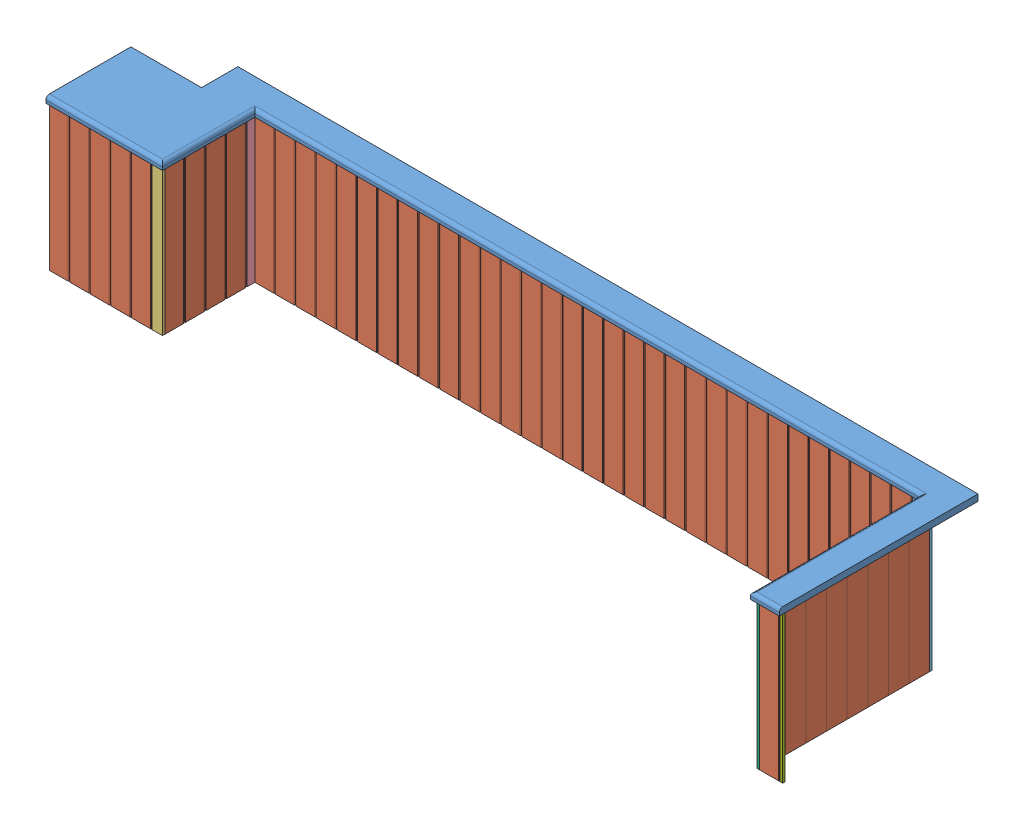
SolidWorks assembly Brüstung, configuration Standard. Lengths in mm.
Overall size (4890 900 1170).
56 component instances, 7 part files, 166 mates.
Components (placement in the parent):
- Platte-1: Platte [Standard] at (1989.1315 795.0064 4189) size (4774 38 1170)
- Wandbrett-1: Wandbrett [Standard] at (-2724.3685 795.0064 4876) x (1 0 0) z (0 0 -1) size (131 862 14)
- Wandbrett-2: Wandbrett [Standard] at (-2603.3685 795.0064 4876) x (1 0 0) z (0 0 -1) size (131 862 14)
- Wandbrett-3: Wandbrett [Standard] at (-2482.3685 795.0064 4876) x (1 0 0) z (0 0 -1) size (131 862 14)
- Wandbrett-4: Wandbrett [Standard] at (-2361.3685 795.0064 4876) x (1 0 0) z (0 0 -1) size (131 862 14)
- Wandbrett-Ecke1-1: Wandbrett-Ecke1 [Standard] at (-2119.3685 795.0064 4876) x (1 0 0) z (0 0 -1) size (131 862 14)
- Wandbrett-6: Wandbrett [Standard] at (-2125.8685 795.0064 4808.5) x (0 0 -1) z (-1 0 0) size (131 862 14)
- Wandbrett-7: Wandbrett [Standard] at (-2125.8685 795.0064 4687.5) x (0 0 -1) z (-1 0 0) size (131 862 14)
- Wandbrett-8: Wandbrett [Standard] at (-2125.8685 795.0064 4566.5) x (0 0 -1) z (-1 0 0) size (131 862 14)
- Wandbrett-9: Wandbrett [Standard] at (-2125.8685 795.0064 4445.5) x (0 0 -1) z (-1 0 0) size (131 862 14)
- Wandbrett-Ecke2-1: Wandbrett-Ecke2 [Standard] at (-2125.8685 795.0064 4324.5) x (0 0 -1) z (-1 0 0) size (60 862 14)
- Wandbrett-11: Wandbrett [Standard] at (-2058.3685 795.0064 4332) x (1 0 0) z (0 0 -1) size (131 862 14)
- Wandbrett-12: Wandbrett [Standard] at (-1937.3685 795.0064 4332) x (1 0 0) z (0 0 -1) size (131 862 14)
- Wandbrett-13: Wandbrett [Standard] at (-1816.3685 795.0064 4332) x (1 0 0) z (0 0 -1) size (131 862 14)
- Wandbrett-14: Wandbrett [Standard] at (-1695.3685 795.0064 4332) x (1 0 0) z (0 0 -1) size (131 862 14)
- Wandbrett-15: Wandbrett [Standard] at (-1574.3685 795.0064 4332) x (1 0 0) z (0 0 -1) size (131 862 14)
- Wandbrett-16: Wandbrett [Standard] at (-1453.3685 795.0064 4332) x (1 0 0) z (0 0 -1) size (131 862 14)
- Wandbrett-17: Wandbrett [Standard] at (-1332.3685 795.0064 4332) x (1 0 0) z (0 0 -1) size (131 862 14)
- Wandbrett-18: Wandbrett [Standard] at (-1211.3685 795.0064 4332) x (1 0 0) z (0 0 -1) size (131 862 14)
- Wandbrett-19: Wandbrett [Standard] at (-1090.3685 795.0064 4332) x (1 0 0) z (0 0 -1) size (131 862 14)
- Wandbrett-20: Wandbrett [Standard] at (-969.3685 795.0064 4332) x (1 0 0) z (0 0 -1) size (131 862 14)
- Wandbrett-21: Wandbrett [Standard] at (-848.3685 795.0064 4332) x (1 0 0) z (0 0 -1) size (131 862 14)
- Wandbrett-22: Wandbrett [Standard] at (-727.3685 795.0064 4332) x (1 0 0) z (0 0 -1) size (131 862 14)
- Wandbrett-23: Wandbrett [Standard] at (-606.3685 795.0064 4332) x (1 0 0) z (0 0 -1) size (131 862 14)
- Wandbrett-24: Wandbrett [Standard] at (-485.3685 795.0064 4332) x (1 0 0) z (0 0 -1) size (131 862 14)
- Wandbrett-25: Wandbrett [Standard] at (-364.3685 795.0064 4332) x (1 0 0) z (0 0 -1) size (131 862 14)
- Wandbrett-26: Wandbrett [Standard] at (-243.3685 795.0064 4332) x (1 0 0) z (0 0 -1) size (131 862 14)
- Wandbrett-27: Wandbrett [Standard] at (-122.3685 795.0064 4332) x (1 0 0) z (0 0 -1) size (131 862 14)
- Wandbrett-28: Wandbrett [Standard] at (-1.3685 795.0064 4332) x (1 0 0) z (0 0 -1) size (131 862 14)
- Wandbrett-29: Wandbrett [Standard] at (119.6315 795.0064 4332) x (1 0 0) z (0 0 -1) size (131 862 14)
- Wandbrett-30: Wandbrett [Standard] at (240.6315 795.0064 4332) x (1 0 0) z (0 0 -1) size (131 862 14)
- Wandbrett-31: Wandbrett [Standard] at (361.6315 795.0064 4332) x (1 0 0) z (0 0 -1) size (131 862 14)
- Wandbrett-32: Wandbrett [Standard] at (482.6315 795.0064 4332) x (1 0 0) z (0 0 -1) size (131 862 14)
- Wandbrett-33: Wandbrett [Standard] at (603.6315 795.0064 4332) x (1 0 0) z (0 0 -1) size (131 862 14)
- Wandbrett-34: Wandbrett [Standard] at (724.6315 795.0064 4332) x (1 0 0) z (0 0 -1) size (131 862 14)
- Wandbrett-35: Wandbrett [Standard] at (845.6315 795.0064 4332) x (1 0 0) z (0 0 -1) size (131 862 14)
- Wandbrett-36: Wandbrett [Standard] at (966.6315 795.0064 4332) x (1 0 0) z (0 0 -1) size (131 862 14)
- Wandbrett-37: Wandbrett [Standard] at (1087.6315 795.0064 4332) x (1 0 0) z (0 0 -1) size (131 862 14)
- Wandbrett-38: Wandbrett [Standard] at (1208.6315 795.0064 4332) x (1 0 0) z (0 0 -1) size (131 862 14)
- Wandbrett-39: Wandbrett [Standard] at (1329.6315 795.0064 4332) x (1 0 0) z (0 0 -1) size (131 862 14)
- Wandbrett-40: Wandbrett [Standard] at (1450.6315 795.0064 4332) x (1 0 0) z (0 0 -1) size (131 862 14)
- Wandbrett-41: Wandbrett [Standard] at (1571.6315 795.0064 4332) x (1 0 0) z (0 0 -1) size (131 862 14)
- Wandbrett-42: Wandbrett [Standard] at (1692.6315 795.0064 4332) x (1 0 0) z (0 0 -1) size (131 862 14)
- Wandbrett-43: Wandbrett [Standard] at (-2240.3685 795.0064 4876) x (1 0 0) z (0 0 -1) size (131 862 14)
- Wandbrett-Ecke3-1: Wandbrett-Ecke3 [Standard] at (1813.6315 795.0064 4332) x (1 0 0) z (0 0 -1) size (131 862 14)
- Wandbrett-44: Wandbrett [Standard] at (1846.1315 795.0064 4399.5) x (0 0 1) z (1 0 0) size (131 862 14)
- Wandbrett-45: Wandbrett [Standard] at (1846.1315 795.0064 4520.5) x (0 0 1) z (1 0 0) size (131 862 14)
- Wandbrett-46: Wandbrett [Standard] at (1846.1315 795.0064 4641.5) x (0 0 1) z (1 0 0) size (131 862 14)
- Wandbrett-47: Wandbrett [Standard] at (1846.1315 795.0064 4762.5) x (0 0 1) z (1 0 0) size (131 862 14)
- Wandbrett-48: Wandbrett [Standard] at (1846.1315 795.0064 4883.5) x (0 0 1) z (1 0 0) size (131 862 14)
- Wandbrett-49: Wandbrett [Standard] at (1846.1315 795.0064 5004.5) x (0 0 1) z (1 0 0) size (131 862 14)
- Wandbrett-50: Wandbrett [Standard] at (1846.1315 795.0064 5125.5) x (0 0 1) z (1 0 0) size (131 862 14)
- Wandbrett-51: Wandbrett [Standard] at (1846.1315 795.0064 5246.5) x (0 0 1) z (1 0 0) size (131 862 14)
- Wandbrett-Ecke4-1: Wandbrett-Ecke4 [Standard] at (1846.1315 795.0064 5367.5) x (0 0 1) z (1 0 0) size (32 862 14)
- Wandbrett-52: Wandbrett [Standard] at (1913.6315 795.0064 5332) x (1 0 0) z (0 0 -1) size (131 862 14)
- Wandbrett-Ecke5-1: Wandbrett-Ecke5 [Standard] at (2034.6315 795.0064 5332) x (1 0 0) z (0 0 -1) size (131 862 14)
Mates (geometry in assembly coordinates):
- Deckungsgleich1: coincident anti-aligned: plane of Platte-1 through (1989.1315 795.0064 4189) normal (0 -1 0); plane of Wandbrett-1 through (-2674.8685 795.0064 4879) normal (0 1 0)
- Deckungsgleich2: coincident anti-aligned: plane of Platte-1 through (1989.1315 795.0064 4189) normal (0 -1 0); plane of Wandbrett-2 through (-2553.8685 795.0064 4879) normal (0 1 0)
- Deckungsgleich3: coincident anti-aligned: plane of Platte-1 through (1989.1315 795.0064 4189) normal (0 -1 0); plane of Wandbrett-3 through (-2432.8685 795.0064 4879) normal (0 1 0)
- Deckungsgleich4: coincident anti-aligned: plane of Platte-1 through (1989.1315 795.0064 4189) normal (0 -1 0); plane of Wandbrett-4 through (-2311.8685 795.0064 4879) normal (0 1 0)
- Parallel1: parallel aligned: plane of Platte-1 through (-2784.8685 833.0064 4903) normal (0 0 1); plane of Wandbrett-1 through (-2674.8685 -66.9936 4883) normal (0 0 1)
- Abstand2: distance = 20 mm aligned: plane of Wandbrett-1 through (-2674.8685 -66.9936 4883) normal (0 0 1); plane of Platte-1 through (-2784.8685 833.0064 4903) normal (0 0 1)
- Deckungsgleich9: coincident aligned: plane of Platte-1 through (-2784.8685 833.0064 4903) normal (-1 0 0); plane of Wandbrett-1 through (-2784.8685 -66.9936 4869) normal (-1 0 0)
- Deckungsgleich10: coincident anti-aligned: plane of Wandbrett-1 through (-2663.8685 -66.9936 4878) normal (0 0 1); plane of Wandbrett-2 through (-2653.8685 -66.9936 4878) normal (0 0 -1)
- Deckungsgleich11: coincident anti-aligned: plane of Wandbrett-2 through (-2542.8685 -66.9936 4878) normal (0 0 1); plane of Wandbrett-3 through (-2532.8685 -66.9936 4878) normal (0 0 -1)
- Deckungsgleich12: coincident anti-aligned: plane of Wandbrett-3 through (-2421.8685 -66.9936 4878) normal (0 0 1); plane of Wandbrett-4 through (-2411.8685 -66.9936 4878) normal (0 0 -1)
- Deckungsgleich14: coincident anti-aligned: plane of Wandbrett-1 through (-2653.8685 -66.9936 4878) normal (1 0 0); plane of Wandbrett-2 through (-2653.8685 -66.9936 4874) normal (-1 0 0)
- Deckungsgleich15: coincident anti-aligned: plane of Wandbrett-2 through (-2532.8685 -66.9936 4878) normal (1 0 0); plane of Wandbrett-3 through (-2532.8685 -66.9936 4874) normal (-1 0 0)
- Deckungsgleich16: coincident anti-aligned: plane of Wandbrett-3 through (-2411.8685 -66.9936 4878) normal (1 0 0); plane of Wandbrett-4 through (-2411.8685 -66.9936 4874) normal (-1 0 0)
- Deckungsgleich18: coincident anti-aligned: plane of Platte-1 through (1989.1315 795.0064 4189) normal (0 -1 0); plane of Wandbrett-Ecke1-1 through (-2069.8685 795.0064 4879) normal (0 1 0)
- Deckungsgleich21: coincident anti-aligned: plane of Platte-1 through (1989.1315 795.0064 4189) normal (0 -1 0); plane of Wandbrett-6 through (-2122.8685 795.0064 4759) normal (0 1 0)
- Deckungsgleich22: coincident anti-aligned: plane of Platte-1 through (1989.1315 795.0064 4189) normal (0 -1 0); plane of Wandbrett-7 through (-2122.8685 795.0064 4638) normal (0 1 0)
- Deckungsgleich23: coincident anti-aligned: plane of Platte-1 through (1989.1315 795.0064 4189) normal (0 -1 0); plane of Wandbrett-8 through (-2122.8685 795.0064 4517) normal (0 1 0)
- Deckungsgleich24: coincident anti-aligned: plane of Platte-1 through (1989.1315 795.0064 4189) normal (0 -1 0); plane of Wandbrett-9 through (-2122.8685 795.0064 4396) normal (0 1 0)
- Deckungsgleich26: coincident anti-aligned: plane of Wandbrett-Ecke1-1 through (-2058.8685 -66.9936 4869) normal (0 0 -1); plane of Wandbrett-6 through (-2132.8685 -66.9936 4869) normal (0 0 1)
- Deckungsgleich27: coincident aligned: plane of Wandbrett-Ecke1-1 through (-2118.8685 -204.9936 4869) normal (1 0 0); plane of Wandbrett-6 through (-2118.8685 -66.9936 4759) normal (1 0 0)
- Deckungsgleich28: coincident anti-aligned: plane of Wandbrett-6 through (-2123.8685 -66.9936 4748) normal (1 0 0); plane of Wandbrett-7 through (-2123.8685 -66.9936 4738) normal (-1 0 0)
- Deckungsgleich29: coincident anti-aligned: plane of Wandbrett-7 through (-2123.8685 -66.9936 4627) normal (1 0 0); plane of Wandbrett-8 through (-2123.8685 -66.9936 4617) normal (-1 0 0)
- Deckungsgleich30: coincident anti-aligned: plane of Wandbrett-8 through (-2123.8685 -66.9936 4506) normal (1 0 0); plane of Wandbrett-9 through (-2123.8685 -66.9936 4496) normal (-1 0 0)
- Deckungsgleich32: coincident anti-aligned: plane of Wandbrett-6 through (-2123.8685 -66.9936 4738) normal (0 0 -1); plane of Wandbrett-7 through (-2127.8685 -66.9936 4738) normal (0 0 1)
- Deckungsgleich33: coincident anti-aligned: plane of Wandbrett-7 through (-2123.8685 -66.9936 4617) normal (0 0 -1); plane of Wandbrett-8 through (-2127.8685 -66.9936 4617) normal (0 0 1)
- Deckungsgleich34: coincident anti-aligned: plane of Wandbrett-8 through (-2123.8685 -66.9936 4496) normal (0 0 -1); plane of Wandbrett-9 through (-2127.8685 -66.9936 4496) normal (0 0 1)
- Deckungsgleich36: coincident anti-aligned: plane of Platte-1 through (1989.1315 795.0064 4189) normal (0 -1 0); plane of Wandbrett-Ecke2-1 through (-2122.8685 795.0064 4275) normal (0 1 0)
- Deckungsgleich37: coincident anti-aligned: plane of Wandbrett-9 through (-2123.8685 -66.9936 4385) normal (1 0 0); plane of Wandbrett-Ecke2-1 through (-2123.8685 -66.9936 4375) normal (-1 0 0)
- Deckungsgleich38: coincident anti-aligned: plane of Wandbrett-9 through (-2123.8685 -66.9936 4375) normal (0 0 -1); plane of Wandbrett-Ecke2-1 through (-2127.8685 -66.9936 4375) normal (0 0 1)
- Deckungsgleich39: coincident anti-aligned: plane of Platte-1 through (1989.1315 795.0064 4189) normal (0 -1 0); plane of Wandbrett-11 through (-2008.8685 795.0064 4335) normal (0 1 0)
- Deckungsgleich40: coincident anti-aligned: plane of Platte-1 through (1989.1315 795.0064 4189) normal (0 -1 0); plane of Wandbrett-12 through (-1887.8685 795.0064 4335) normal (0 1 0)
- Deckungsgleich41: coincident anti-aligned: plane of Platte-1 through (1989.1315 795.0064 4189) normal (0 -1 0); plane of Wandbrett-13 through (-1766.8685 795.0064 4335) normal (0 1 0)
- Deckungsgleich42: coincident anti-aligned: plane of Platte-1 through (1989.1315 795.0064 4189) normal (0 -1 0); plane of Wandbrett-14 through (-1645.8685 795.0064 4335) normal (0 1 0)
- Deckungsgleich43: coincident anti-aligned: plane of Platte-1 through (1989.1315 795.0064 4189) normal (0 -1 0); plane of Wandbrett-15 through (-1524.8685 795.0064 4335) normal (0 1 0)
- Deckungsgleich44: coincident anti-aligned: plane of Platte-1 through (1989.1315 795.0064 4189) normal (0 -1 0); plane of Wandbrett-16 through (-1403.8685 795.0064 4335) normal (0 1 0)
- Deckungsgleich45: coincident anti-aligned: plane of Platte-1 through (1989.1315 795.0064 4189) normal (0 -1 0); plane of Wandbrett-17 through (-1282.8685 795.0064 4335) normal (0 1 0)
- Deckungsgleich46: coincident anti-aligned: plane of Platte-1 through (1989.1315 795.0064 4189) normal (0 -1 0); plane of Wandbrett-18 through (-1161.8685 795.0064 4335) normal (0 1 0)
- Deckungsgleich47: coincident anti-aligned: plane of Platte-1 through (1989.1315 795.0064 4189) normal (0 -1 0); plane of Wandbrett-19 through (-1040.8685 795.0064 4335) normal (0 1 0)
- Deckungsgleich48: coincident anti-aligned: plane of Platte-1 through (1989.1315 795.0064 4189) normal (0 -1 0); plane of Wandbrett-20 through (-919.8685 795.0064 4335) normal (0 1 0)
- Deckungsgleich49: coincident anti-aligned: plane of Platte-1 through (1989.1315 795.0064 4189) normal (0 -1 0); plane of Wandbrett-21 through (-798.8685 795.0064 4335) normal (0 1 0)
- Deckungsgleich50: coincident anti-aligned: plane of Platte-1 through (1989.1315 795.0064 4189) normal (0 -1 0); plane of Wandbrett-22 through (-677.8685 795.0064 4335) normal (0 1 0)
- Deckungsgleich51: coincident anti-aligned: plane of Platte-1 through (1989.1315 795.0064 4189) normal (0 -1 0); plane of Wandbrett-23 through (-556.8685 795.0064 4335) normal (0 1 0)
- Deckungsgleich52: coincident anti-aligned: plane of Platte-1 through (1989.1315 795.0064 4189) normal (0 -1 0); plane of Wandbrett-24 through (-435.8685 795.0064 4335) normal (0 1 0)
- Deckungsgleich53: coincident anti-aligned: plane of Platte-1 through (1989.1315 795.0064 4189) normal (0 -1 0); plane of Wandbrett-25 through (-314.8685 795.0064 4335) normal (0 1 0)
- Deckungsgleich54: coincident anti-aligned: plane of Platte-1 through (1989.1315 795.0064 4189) normal (0 -1 0); plane of Wandbrett-26 through (-193.8685 795.0064 4335) normal (0 1 0)
- Deckungsgleich55: coincident anti-aligned: plane of Platte-1 through (1989.1315 795.0064 4189) normal (0 -1 0); plane of Wandbrett-27 through (-72.8685 795.0064 4335) normal (0 1 0)
- Deckungsgleich56: coincident anti-aligned: plane of Platte-1 through (1989.1315 795.0064 4189) normal (0 -1 0); plane of Wandbrett-28 through (48.1315 795.0064 4335) normal (0 1 0)
- Deckungsgleich57: coincident anti-aligned: plane of Platte-1 through (1989.1315 795.0064 4189) normal (0 -1 0); plane of Wandbrett-29 through (169.1315 795.0064 4335) normal (0 1 0)
- Deckungsgleich58: coincident anti-aligned: plane of Platte-1 through (1989.1315 795.0064 4189) normal (0 -1 0); plane of Wandbrett-30 through (290.1315 795.0064 4335) normal (0 1 0)
- Deckungsgleich59: coincident anti-aligned: plane of Platte-1 through (1989.1315 795.0064 4189) normal (0 -1 0); plane of Wandbrett-31 through (411.1315 795.0064 4335) normal (0 1 0)
- Deckungsgleich60: coincident anti-aligned: plane of Platte-1 through (1989.1315 795.0064 4189) normal (0 -1 0); plane of Wandbrett-32 through (532.1315 795.0064 4335) normal (0 1 0)
- Deckungsgleich61: coincident anti-aligned: plane of Platte-1 through (1989.1315 795.0064 4189) normal (0 -1 0); plane of Wandbrett-33 through (653.1315 795.0064 4335) normal (0 1 0)
- Deckungsgleich62: coincident anti-aligned: plane of Platte-1 through (1989.1315 795.0064 4189) normal (0 -1 0); plane of Wandbrett-34 through (774.1315 795.0064 4335) normal (0 1 0)
- Deckungsgleich63: coincident anti-aligned: plane of Platte-1 through (1989.1315 795.0064 4189) normal (0 -1 0); plane of Wandbrett-35 through (895.1315 795.0064 4335) normal (0 1 0)
- Deckungsgleich64: coincident anti-aligned: plane of Platte-1 through (1989.1315 795.0064 4189) normal (0 -1 0); plane of Wandbrett-36 through (1016.1315 795.0064 4335) normal (0 1 0)
- Deckungsgleich65: coincident anti-aligned: plane of Platte-1 through (1989.1315 795.0064 4189) normal (0 -1 0); plane of Wandbrett-37 through (1137.1315 795.0064 4335) normal (0 1 0)
- Deckungsgleich66: coincident anti-aligned: plane of Platte-1 through (1989.1315 795.0064 4189) normal (0 -1 0); plane of Wandbrett-38 through (1258.1315 795.0064 4335) normal (0 1 0)
- Deckungsgleich67: coincident anti-aligned: plane of Platte-1 through (1989.1315 795.0064 4189) normal (0 -1 0); plane of Wandbrett-39 through (1379.1315 795.0064 4335) normal (0 1 0)
- Deckungsgleich68: coincident anti-aligned: plane of Platte-1 through (1989.1315 795.0064 4189) normal (0 -1 0); plane of Wandbrett-40 through (1500.1315 795.0064 4335) normal (0 1 0)
- Deckungsgleich69: coincident anti-aligned: plane of Platte-1 through (1989.1315 795.0064 4189) normal (0 -1 0); plane of Wandbrett-41 through (1621.1315 795.0064 4335) normal (0 1 0)
- Deckungsgleich70: coincident anti-aligned: plane of Platte-1 through (1989.1315 795.0064 4189) normal (0 -1 0); plane of Wandbrett-42 through (1742.1315 795.0064 4335) normal (0 1 0)
- Deckungsgleich71: coincident anti-aligned: plane of Wandbrett-Ecke2-1 through (-2118.8685 -66.9936 4275) normal (1 0 0); plane of Wandbrett-11 through (-2118.8685 -66.9936 4334) normal (-1 0 0)
- Deckungsgleich72: coincident anti-aligned: plane of Wandbrett-11 through (-1997.8685 -66.9936 4334) normal (0 0 1); plane of Wandbrett-12 through (-1987.8685 -66.9936 4334) normal (0 0 -1)
- Deckungsgleich73: coincident anti-aligned: plane of Wandbrett-12 through (-1876.8685 -66.9936 4334) normal (0 0 1); plane of Wandbrett-13 through (-1866.8685 -66.9936 4334) normal (0 0 -1)
- Deckungsgleich74: coincident anti-aligned: plane of Wandbrett-13 through (-1755.8685 -66.9936 4334) normal (0 0 1); plane of Wandbrett-14 through (-1745.8685 -66.9936 4334) normal (0 0 -1)
- Deckungsgleich75: coincident anti-aligned: plane of Wandbrett-14 through (-1634.8685 -66.9936 4334) normal (0 0 1); plane of Wandbrett-15 through (-1624.8685 -66.9936 4334) normal (0 0 -1)
- Deckungsgleich76: coincident anti-aligned: plane of Wandbrett-15 through (-1513.8685 -66.9936 4334) normal (0 0 1); plane of Wandbrett-16 through (-1503.8685 -66.9936 4334) normal (0 0 -1)
- Deckungsgleich77: coincident anti-aligned: plane of Wandbrett-16 through (-1392.8685 -66.9936 4334) normal (0 0 1); plane of Wandbrett-17 through (-1382.8685 -66.9936 4334) normal (0 0 -1)
- Deckungsgleich78: coincident anti-aligned: plane of Wandbrett-17 through (-1271.8685 -66.9936 4334) normal (0 0 1); plane of Wandbrett-18 through (-1261.8685 -66.9936 4334) normal (0 0 -1)
- Deckungsgleich79: coincident anti-aligned: plane of Wandbrett-18 through (-1150.8685 -66.9936 4334) normal (0 0 1); plane of Wandbrett-19 through (-1140.8685 -66.9936 4334) normal (0 0 -1)
- Deckungsgleich80: coincident anti-aligned: plane of Wandbrett-19 through (-1029.8685 -66.9936 4334) normal (0 0 1); plane of Wandbrett-20 through (-1019.8685 -66.9936 4334) normal (0 0 -1)
- Deckungsgleich81: coincident anti-aligned: plane of Wandbrett-20 through (-908.8685 -66.9936 4334) normal (0 0 1); plane of Wandbrett-21 through (-898.8685 -66.9936 4334) normal (0 0 -1)
- Deckungsgleich82: coincident anti-aligned: plane of Wandbrett-21 through (-787.8685 -66.9936 4334) normal (0 0 1); plane of Wandbrett-22 through (-777.8685 -66.9936 4334) normal (0 0 -1)
- Deckungsgleich83: coincident anti-aligned: plane of Wandbrett-22 through (-666.8685 -66.9936 4334) normal (0 0 1); plane of Wandbrett-23 through (-656.8685 -66.9936 4334) normal (0 0 -1)
- Deckungsgleich84: coincident anti-aligned: plane of Wandbrett-23 through (-545.8685 -66.9936 4334) normal (0 0 1); plane of Wandbrett-24 through (-535.8685 -66.9936 4334) normal (0 0 -1)
- Deckungsgleich85: coincident anti-aligned: plane of Wandbrett-24 through (-424.8685 -66.9936 4334) normal (0 0 1); plane of Wandbrett-25 through (-414.8685 -66.9936 4334) normal (0 0 -1)
- Deckungsgleich86: coincident anti-aligned: plane of Wandbrett-25 through (-303.8685 -66.9936 4334) normal (0 0 1); plane of Wandbrett-26 through (-293.8685 -66.9936 4334) normal (0 0 -1)
- Deckungsgleich87: coincident anti-aligned: plane of Wandbrett-26 through (-182.8685 -66.9936 4334) normal (0 0 1); plane of Wandbrett-27 through (-172.8685 -66.9936 4334) normal (0 0 -1)
- Deckungsgleich88: coincident anti-aligned: plane of Wandbrett-27 through (-61.8685 -66.9936 4334) normal (0 0 1); plane of Wandbrett-28 through (-51.8685 -66.9936 4334) normal (0 0 -1)
- Deckungsgleich90: coincident anti-aligned: plane of Wandbrett-28 through (59.1315 -66.9936 4334) normal (0 0 1); plane of Wandbrett-29 through (69.1315 -66.9936 4334) normal (0 0 -1)
- Deckungsgleich91: coincident anti-aligned: plane of Wandbrett-29 through (180.1315 -66.9936 4334) normal (0 0 1); plane of Wandbrett-30 through (190.1315 -66.9936 4334) normal (0 0 -1)
- Deckungsgleich92: coincident anti-aligned: plane of Wandbrett-30 through (301.1315 -66.9936 4334) normal (0 0 1); plane of Wandbrett-31 through (311.1315 -66.9936 4334) normal (0 0 -1)
- Deckungsgleich93: coincident anti-aligned: plane of Wandbrett-31 through (422.1315 -66.9936 4334) normal (0 0 1); plane of Wandbrett-32 through (432.1315 -66.9936 4334) normal (0 0 -1)
- Deckungsgleich94: coincident anti-aligned: plane of Wandbrett-32 through (543.1315 -66.9936 4334) normal (0 0 1); plane of Wandbrett-33 through (553.1315 -66.9936 4334) normal (0 0 -1)
- Deckungsgleich95: coincident anti-aligned: plane of Wandbrett-33 through (664.1315 -66.9936 4334) normal (0 0 1); plane of Wandbrett-34 through (674.1315 -66.9936 4334) normal (0 0 -1)
- Deckungsgleich96: coincident anti-aligned: plane of Wandbrett-34 through (785.1315 -66.9936 4334) normal (0 0 1); plane of Wandbrett-35 through (795.1315 -66.9936 4334) normal (0 0 -1)
- Deckungsgleich97: coincident anti-aligned: plane of Wandbrett-35 through (906.1315 -66.9936 4334) normal (0 0 1); plane of Wandbrett-36 through (916.1315 -66.9936 4334) normal (0 0 -1)
- Deckungsgleich98: coincident anti-aligned: plane of Wandbrett-36 through (1027.1315 -66.9936 4334) normal (0 0 1); plane of Wandbrett-37 through (1037.1315 -66.9936 4334) normal (0 0 -1)
- Deckungsgleich99: coincident anti-aligned: plane of Wandbrett-37 through (1148.1315 -66.9936 4334) normal (0 0 1); plane of Wandbrett-38 through (1158.1315 -66.9936 4334) normal (0 0 -1)
- Deckungsgleich100: coincident anti-aligned: plane of Wandbrett-38 through (1269.1315 -66.9936 4334) normal (0 0 1); plane of Wandbrett-39 through (1279.1315 -66.9936 4334) normal (0 0 -1)
- Deckungsgleich101: coincident anti-aligned: plane of Wandbrett-39 through (1390.1315 -66.9936 4334) normal (0 0 1); plane of Wandbrett-40 through (1400.1315 -66.9936 4334) normal (0 0 -1)
- Deckungsgleich102: coincident anti-aligned: plane of Wandbrett-40 through (1511.1315 -66.9936 4334) normal (0 0 1); plane of Wandbrett-41 through (1521.1315 -66.9936 4334) normal (0 0 -1)
- Deckungsgleich103: coincident anti-aligned: plane of Wandbrett-41 through (1632.1315 -66.9936 4334) normal (0 0 1); plane of Wandbrett-42 through (1642.1315 -66.9936 4334) normal (0 0 -1)
- Deckungsgleich104: coincident aligned: plane of Wandbrett-Ecke2-1 through (-2118.8685 -204.9936 4325) normal (0 0 -1); plane of Wandbrett-11 through (-1997.8685 -66.9936 4325) normal (0 0 -1)
- Deckungsgleich105: coincident anti-aligned: plane of Wandbrett-11 through (-1987.8685 -66.9936 4334) normal (1 0 0); plane of Wandbrett-12 through (-1987.8685 -66.9936 4330) normal (-1 0 0)
- Deckungsgleich106: coincident anti-aligned: plane of Wandbrett-12 through (-1866.8685 -66.9936 4334) normal (1 0 0); plane of Wandbrett-13 through (-1866.8685 -66.9936 4330) normal (-1 0 0)
- Deckungsgleich107: coincident anti-aligned: plane of Wandbrett-13 through (-1745.8685 -66.9936 4334) normal (1 0 0); plane of Wandbrett-14 through (-1745.8685 -66.9936 4330) normal (-1 0 0)
- Deckungsgleich108: coincident anti-aligned: plane of Wandbrett-14 through (-1624.8685 -66.9936 4334) normal (1 0 0); plane of Wandbrett-15 through (-1624.8685 -66.9936 4330) normal (-1 0 0)
- Deckungsgleich109: coincident anti-aligned: plane of Wandbrett-15 through (-1503.8685 -66.9936 4334) normal (1 0 0); plane of Wandbrett-16 through (-1503.8685 -66.9936 4330) normal (-1 0 0)
- Deckungsgleich110: coincident anti-aligned: plane of Wandbrett-16 through (-1382.8685 -66.9936 4334) normal (1 0 0); plane of Wandbrett-17 through (-1382.8685 -66.9936 4330) normal (-1 0 0)
- Deckungsgleich111: coincident anti-aligned: plane of Wandbrett-17 through (-1261.8685 -66.9936 4334) normal (1 0 0); plane of Wandbrett-18 through (-1261.8685 -66.9936 4330) normal (-1 0 0)
- Deckungsgleich112: coincident anti-aligned: plane of Wandbrett-18 through (-1140.8685 -66.9936 4334) normal (1 0 0); plane of Wandbrett-19 through (-1140.8685 -66.9936 4330) normal (-1 0 0)
- Deckungsgleich113: coincident anti-aligned: plane of Wandbrett-19 through (-1019.8685 -66.9936 4334) normal (1 0 0); plane of Wandbrett-20 through (-1019.8685 -66.9936 4330) normal (-1 0 0)
- Deckungsgleich114: coincident anti-aligned: plane of Wandbrett-20 through (-898.8685 -66.9936 4334) normal (1 0 0); plane of Wandbrett-21 through (-898.8685 -66.9936 4330) normal (-1 0 0)
- Deckungsgleich115: coincident anti-aligned: plane of Wandbrett-21 through (-777.8685 -66.9936 4334) normal (1 0 0); plane of Wandbrett-22 through (-777.8685 -66.9936 4330) normal (-1 0 0)
- Deckungsgleich117: coincident anti-aligned: plane of Wandbrett-22 through (-656.8685 -66.9936 4334) normal (1 0 0); plane of Wandbrett-23 through (-656.8685 -66.9936 4330) normal (-1 0 0)
- Deckungsgleich118: coincident anti-aligned: plane of Wandbrett-23 through (-535.8685 -66.9936 4334) normal (1 0 0); plane of Wandbrett-24 through (-535.8685 -66.9936 4330) normal (-1 0 0)
- Deckungsgleich119: coincident anti-aligned: plane of Wandbrett-24 through (-414.8685 -66.9936 4334) normal (1 0 0); plane of Wandbrett-25 through (-414.8685 -66.9936 4330) normal (-1 0 0)
- Deckungsgleich121: coincident anti-aligned: plane of Wandbrett-25 through (-293.8685 -66.9936 4334) normal (1 0 0); plane of Wandbrett-26 through (-293.8685 -66.9936 4330) normal (-1 0 0)
- Deckungsgleich122: coincident anti-aligned: plane of Wandbrett-26 through (-172.8685 -66.9936 4334) normal (1 0 0); plane of Wandbrett-27 through (-172.8685 -66.9936 4330) normal (-1 0 0)
- Deckungsgleich123: coincident anti-aligned: plane of Wandbrett-27 through (-51.8685 -66.9936 4334) normal (1 0 0); plane of Wandbrett-28 through (-51.8685 -66.9936 4330) normal (-1 0 0)
- Deckungsgleich124: coincident anti-aligned: plane of Wandbrett-28 through (69.1315 -66.9936 4334) normal (1 0 0); plane of Wandbrett-29 through (69.1315 -66.9936 4330) normal (-1 0 0)
- Deckungsgleich125: coincident anti-aligned: plane of Wandbrett-29 through (190.1315 -66.9936 4334) normal (1 0 0); plane of Wandbrett-30 through (190.1315 -66.9936 4330) normal (-1 0 0)
- Deckungsgleich126: coincident anti-aligned: plane of Wandbrett-30 through (311.1315 -66.9936 4334) normal (1 0 0); plane of Wandbrett-31 through (311.1315 -66.9936 4330) normal (-1 0 0)
- Deckungsgleich127: coincident anti-aligned: plane of Wandbrett-31 through (432.1315 -66.9936 4334) normal (1 0 0); plane of Wandbrett-32 through (432.1315 -66.9936 4330) normal (-1 0 0)
- Deckungsgleich128: coincident anti-aligned: plane of Wandbrett-32 through (553.1315 -66.9936 4334) normal (1 0 0); plane of Wandbrett-33 through (553.1315 -66.9936 4330) normal (-1 0 0)
- Deckungsgleich129: coincident anti-aligned: plane of Wandbrett-33 through (674.1315 -66.9936 4334) normal (1 0 0); plane of Wandbrett-34 through (674.1315 -66.9936 4330) normal (-1 0 0)
- Deckungsgleich130: coincident anti-aligned: plane of Wandbrett-34 through (795.1315 -66.9936 4334) normal (1 0 0); plane of Wandbrett-35 through (795.1315 -66.9936 4330) normal (-1 0 0)
- Deckungsgleich131: coincident anti-aligned: plane of Wandbrett-35 through (916.1315 -66.9936 4334) normal (1 0 0); plane of Wandbrett-36 through (916.1315 -66.9936 4330) normal (-1 0 0)
- Deckungsgleich132: coincident anti-aligned: plane of Wandbrett-36 through (1037.1315 -66.9936 4334) normal (1 0 0); plane of Wandbrett-37 through (1037.1315 -66.9936 4330) normal (-1 0 0)
- Deckungsgleich133: coincident anti-aligned: plane of Wandbrett-37 through (1158.1315 -66.9936 4334) normal (1 0 0); plane of Wandbrett-38 through (1158.1315 -66.9936 4330) normal (-1 0 0)
- Deckungsgleich136: coincident anti-aligned: plane of Wandbrett-38 through (1279.1315 -66.9936 4334) normal (1 0 0); plane of Wandbrett-39 through (1279.1315 -66.9936 4330) normal (-1 0 0)
- Deckungsgleich137: coincident anti-aligned: plane of Wandbrett-39 through (1400.1315 -66.9936 4334) normal (1 0 0); plane of Wandbrett-40 through (1400.1315 -66.9936 4330) normal (-1 0 0)
- Deckungsgleich138: coincident anti-aligned: plane of Wandbrett-40 through (1521.1315 -66.9936 4334) normal (1 0 0); plane of Wandbrett-41 through (1521.1315 -66.9936 4330) normal (-1 0 0)
- Deckungsgleich139: coincident anti-aligned: plane of Wandbrett-41 through (1642.1315 -66.9936 4334) normal (1 0 0); plane of Wandbrett-42 through (1642.1315 -66.9936 4330) normal (-1 0 0)
- Deckungsgleich140: coincident anti-aligned: plane of Platte-1 through (1989.1315 795.0064 4189) normal (0 -1 0); plane of Wandbrett-43 through (-2190.8685 795.0064 4879) normal (0 1 0)
- Deckungsgleich143: coincident anti-aligned: plane of Platte-1 through (1989.1315 795.0064 4189) normal (0 -1 0); plane of Wandbrett-Ecke3-1 through (1863.1315 795.0064 4335) normal (0 1 0)
- Deckungsgleich156: coincident anti-aligned: plane of Platte-1 through (1989.1315 795.0064 4189) normal (0 -1 0); plane of Wandbrett-44 through (1843.1315 795.0064 4449) normal (0 1 0)
- Deckungsgleich157: coincident anti-aligned: plane of Platte-1 through (1989.1315 795.0064 4189) normal (0 -1 0); plane of Wandbrett-45 through (1843.1315 795.0064 4570) normal (0 1 0)
- Deckungsgleich158: coincident anti-aligned: plane of Platte-1 through (1989.1315 795.0064 4189) normal (0 -1 0); plane of Wandbrett-46 through (1843.1315 795.0064 4691) normal (0 1 0)
- Deckungsgleich159: coincident anti-aligned: plane of Platte-1 through (1989.1315 795.0064 4189) normal (0 -1 0); plane of Wandbrett-47 through (1843.1315 795.0064 4812) normal (0 1 0)
- Deckungsgleich160: coincident anti-aligned: plane of Platte-1 through (1989.1315 795.0064 4189) normal (0 -1 0); plane of Wandbrett-48 through (1843.1315 795.0064 4933) normal (0 1 0)
- Deckungsgleich161: coincident anti-aligned: plane of Platte-1 through (1989.1315 795.0064 4189) normal (0 -1 0); plane of Wandbrett-49 through (1843.1315 795.0064 5054) normal (0 1 0)
- Deckungsgleich162: coincident anti-aligned: plane of Platte-1 through (1989.1315 795.0064 4189) normal (0 -1 0); plane of Wandbrett-50 through (1843.1315 795.0064 5175) normal (0 1 0)
- Deckungsgleich163: coincident anti-aligned: plane of Platte-1 through (1989.1315 795.0064 4189) normal (0 -1 0); plane of Wandbrett-51 through (1843.1315 795.0064 5296) normal (0 1 0)
- Deckungsgleich164: coincident anti-aligned: plane of Wandbrett-Ecke3-1 through (1863.1315 -66.9936 4339) normal (0 0 1); plane of Wandbrett-44 through (1844.1315 -66.9936 4339) normal (0 0 -1)
- Deckungsgleich165: coincident aligned: plane of Wandbrett-44 through (1853.1315 -66.9936 4460) normal (1 0 0); plane of Wandbrett-Ecke3-1 through (1853.1315 -204.9936 4325) normal (1 0 0)
- Deckungsgleich166: coincident anti-aligned: plane of Wandbrett-44 through (1844.1315 -66.9936 4460) normal (-1 0 0); plane of Wandbrett-45 through (1844.1315 -66.9936 4470) normal (1 0 0)
- Deckungsgleich167: coincident anti-aligned: plane of Wandbrett-45 through (1844.1315 -66.9936 4581) normal (-1 0 0); plane of Wandbrett-46 through (1844.1315 -66.9936 4591) normal (1 0 0)
- Deckungsgleich168: coincident anti-aligned: plane of Wandbrett-46 through (1844.1315 -66.9936 4702) normal (-1 0 0); plane of Wandbrett-47 through (1844.1315 -66.9936 4712) normal (1 0 0)
- Deckungsgleich169: coincident anti-aligned: plane of Wandbrett-47 through (1844.1315 -66.9936 4823) normal (-1 0 0); plane of Wandbrett-48 through (1844.1315 -66.9936 4833) normal (1 0 0)
- Deckungsgleich170: coincident anti-aligned: plane of Wandbrett-48 through (1844.1315 -66.9936 4944) normal (-1 0 0); plane of Wandbrett-49 through (1844.1315 -66.9936 4954) normal (1 0 0)
- Deckungsgleich171: coincident anti-aligned: plane of Wandbrett-49 through (1844.1315 -66.9936 5065) normal (-1 0 0); plane of Wandbrett-50 through (1844.1315 -66.9936 5075) normal (1 0 0)
- Deckungsgleich172: coincident anti-aligned: plane of Wandbrett-50 through (1844.1315 -66.9936 5186) normal (-1 0 0); plane of Wandbrett-51 through (1844.1315 -66.9936 5196) normal (1 0 0)
- Deckungsgleich173: coincident anti-aligned: plane of Wandbrett-44 through (1844.1315 -66.9936 4470) normal (0 0 1); plane of Wandbrett-45 through (1848.1315 -66.9936 4470) normal (0 0 -1)
- Deckungsgleich174: coincident anti-aligned: plane of Wandbrett-45 through (1844.1315 -66.9936 4591) normal (0 0 1); plane of Wandbrett-46 through (1848.1315 -66.9936 4591) normal (0 0 -1)
- Deckungsgleich175: coincident anti-aligned: plane of Wandbrett-46 through (1844.1315 -66.9936 4712) normal (0 0 1); plane of Wandbrett-47 through (1848.1315 -66.9936 4712) normal (0 0 -1)
- Deckungsgleich176: coincident anti-aligned: plane of Wandbrett-47 through (1844.1315 -66.9936 4833) normal (0 0 1); plane of Wandbrett-48 through (1848.1315 -66.9936 4833) normal (0 0 -1)
- Deckungsgleich177: coincident anti-aligned: plane of Wandbrett-48 through (1844.1315 -66.9936 4954) normal (0 0 1); plane of Wandbrett-49 through (1848.1315 -66.9936 4954) normal (0 0 -1)
- Deckungsgleich179: coincident anti-aligned: plane of Wandbrett-49 through (1844.1315 -66.9936 5075) normal (0 0 1); plane of Wandbrett-50 through (1848.1315 -66.9936 5075) normal (0 0 -1)
- Deckungsgleich180: coincident anti-aligned: plane of Wandbrett-50 through (1844.1315 -66.9936 5196) normal (0 0 1); plane of Wandbrett-51 through (1848.1315 -66.9936 5196) normal (0 0 -1)
- Deckungsgleich181: coincident anti-aligned: plane of Platte-1 through (1989.1315 795.0064 4189) normal (0 -1 0); plane of Wandbrett-Ecke4-1 through (1843.1315 795.0064 5417) normal (0 1 0)
- Deckungsgleich182: coincident anti-aligned: plane of Wandbrett-51 through (1844.1315 -66.9936 5307) normal (-1 0 0); plane of Wandbrett-Ecke4-1 through (1844.1315 -66.9936 5317) normal (1 0 0)
- Deckungsgleich183: coincident anti-aligned: plane of Wandbrett-51 through (1844.1315 -66.9936 5317) normal (0 0 1); plane of Wandbrett-Ecke4-1 through (1848.1315 -66.9936 5317) normal (0 0 -1)
- Deckungsgleich184: coincident anti-aligned: plane of Platte-1 through (1989.1315 795.0064 4189) normal (0 -1 0); plane of Wandbrett-52 through (1963.1315 795.0064 5335) normal (0 1 0)
- Deckungsgleich185: coincident anti-aligned: plane of Wandbrett-Ecke4-1 through (1853.1315 -66.9936 5428) normal (1 0 0); plane of Wandbrett-52 through (1853.1315 -66.9936 5334) normal (-1 0 0)
- Deckungsgleich186: coincident aligned: plane of Wandbrett-Ecke4-1 through (1853.1315 -204.9936 5339) normal (0 0 1); plane of Wandbrett-52 through (1963.1315 -66.9936 5339) normal (0 0 1)
- Deckungsgleich187: coincident anti-aligned: plane of Platte-1 through (1989.1315 795.0064 4189) normal (0 -1 0); plane of Wandbrett-Ecke5-1 through (2084.1315 795.0064 5335) normal (0 1 0)
- Deckungsgleich188: coincident anti-aligned: plane of Wandbrett-52 through (1984.1315 -66.9936 5334) normal (1 0 0); plane of Wandbrett-Ecke5-1 through (1984.1315 -66.9936 5330) normal (-1 0 0)
- Deckungsgleich189: coincident anti-aligned: plane of Wandbrett-52 through (1974.1315 -66.9936 5334) normal (0 0 1); plane of Wandbrett-Ecke5-1 through (1984.1315 -66.9936 5334) normal (0 0 -1)
- Deckungsgleich190: coincident anti-aligned: plane of Wandbrett-4 through (-2300.8685 -66.9936 4878) normal (0 0 1); plane of Wandbrett-43 through (-2290.8685 -66.9936 4878) normal (0 0 -1)
- Deckungsgleich191: coincident anti-aligned: plane of Wandbrett-4 through (-2290.8685 -66.9936 4878) normal (1 0 0); plane of Wandbrett-43 through (-2290.8685 -66.9936 4874) normal (-1 0 0)
- Deckungsgleich193: coincident anti-aligned: plane of Wandbrett-Ecke1-1 through (-2169.8685 -66.9936 4878) normal (0 0 -1); plane of Wandbrett-43 through (-2179.8685 -66.9936 4878) normal (0 0 1)
- Deckungsgleich194: coincident anti-aligned: plane of Wandbrett-Ecke1-1 through (-2169.8685 -66.9936 4874) normal (-1 0 0); plane of Wandbrett-43 through (-2169.8685 -66.9936 4878) normal (1 0 0)
- Deckungsgleich195: coincident anti-aligned: plane of Wandbrett-42 through (1763.1315 -66.9936 4334) normal (1 0 0); plane of Wandbrett-Ecke3-1 through (1763.1315 -66.9936 4330) normal (-1 0 0)
- Deckungsgleich196: coincident anti-aligned: plane of Wandbrett-42 through (1753.1315 -66.9936 4334) normal (0 0 1); plane of Wandbrett-Ecke3-1 through (1763.1315 -66.9936 4334) normal (0 0 -1)
